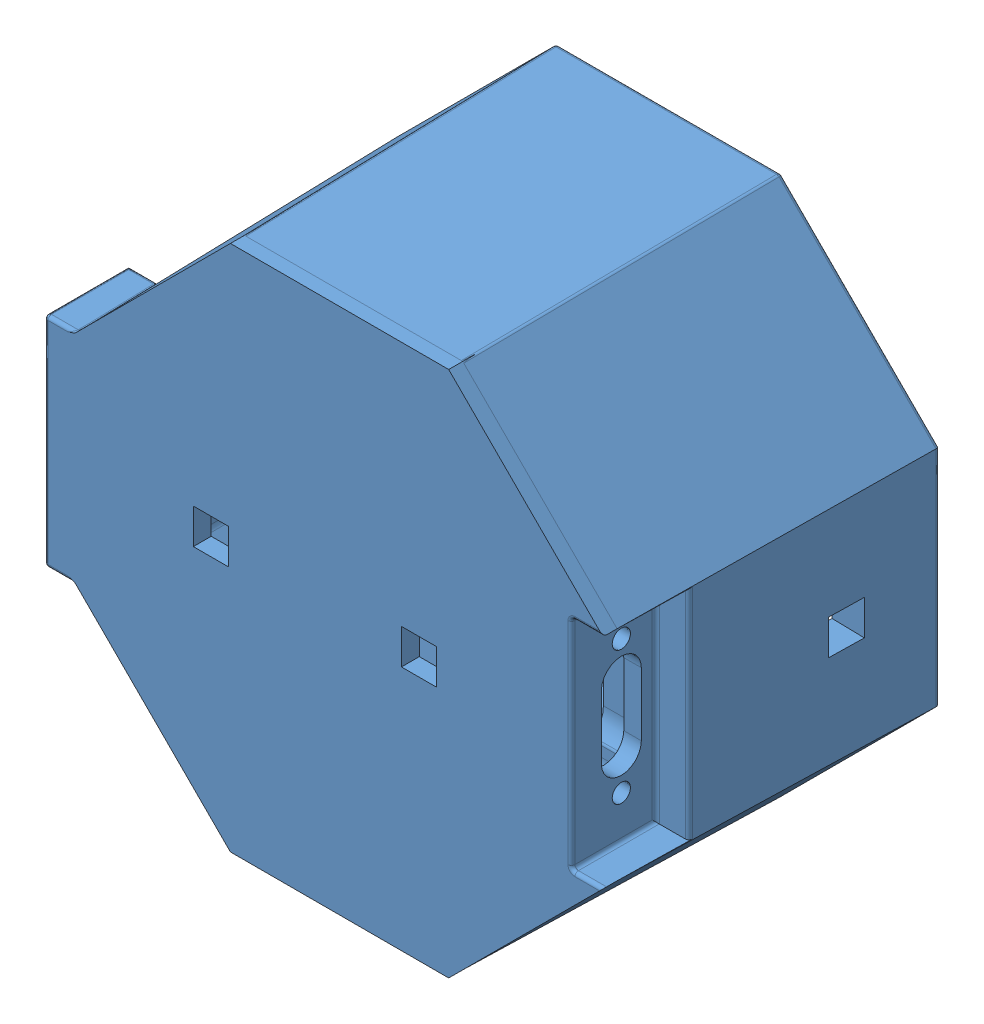
SolidWorks assembly blocprog_seul, configuration Défaut. Lengths in mm.
Overall size (80.4 76.79 47).
7 component instances, 3 part files, 3 mates.
Components (placement in the parent):
- block-1: block [Défaut] at origin size (80.39 76.79 47)
- SWIFT DOCK MINI-4-L-1: SWIFT DOCK MINI-4-L [Défaut] at (-38 -4.5 54.9) x (0 1 0) z (0 0 1) size (24 6.56 8)
  - land body_4 hole_mini-1: land body_4 hole_mini [Défaut] at origin size (24 4.81 8)
  - contact land_sd_mini-1: contact land_sd_mini [Défaut] at (0 3.94 0) x (1 0 0) z (0 1 0) size (2.23 2.23 6.5)
  - contact land_sd_mini-2: contact land_sd_mini [Défaut] at (3 3.94 0) x (1 0 0) z (0 1 0) size (2.23 2.23 6.5)
  - contact land_sd_mini-3: contact land_sd_mini [Défaut] at (6 3.94 0) x (1 0 0) z (0 1 0) size (2.23 2.23 6.5)
  - contact land_sd_mini-4: contact land_sd_mini [Défaut] at (9 3.94 0) x (1 0 0) z (0 1 0) size (2.23 2.23 6.5)
Mates (geometry in assembly coordinates):
- Coïncidente1: coincident aligned: plane of block-1 through (0 0 0) normal (0 1 0); plane of SWIFT DOCK MINI-4-L-1/land body_4 hole_mini-1
- Parallèle2: parallel aligned: plane of SWIFT DOCK MINI-4-L-1/land body_4 hole_mini-1 through (-38 -4.5 54.9) normal (0 0 1); plane of assembly through (0 0 0) normal (0 0 1)
- Coïncidente8: coincident aligned: plane of block-1 through (-42 15.533 50) normal (-1 0 0); plane of SWIFT DOCK MINI-4-L-1/land body_4 hole_mini-1 through (-42 -4.5 54.9) normal (-1 0 0)
